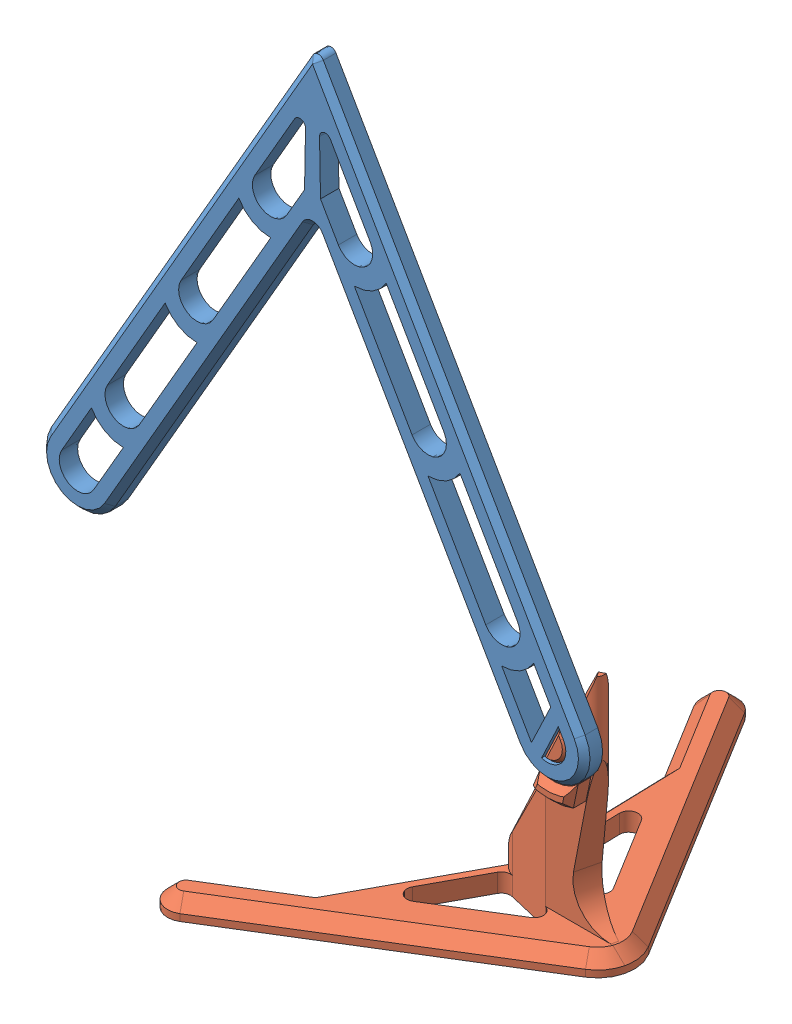
SolidWorks assembly prize_A, configuration Default. Lengths in mm.
Overall size (107.04 112.97 90.43).
2 component instances, 2 part files, 2 mates.
Components (placement in the parent):
- letter_A-1: letter_A [Default] at (-10.7459 59.4947 -8.1672) size (93.65 88.15 3.17)
- stand_A-1: stand_A [Default] at (33.734 -54.4767 -9.6356) x (0.972894 0 0.23125) z (-0.23125 0 0.972894) size (43.2 41.27 82.68)
Mates (geometry in assembly coordinates):
- Coincident1: coincident: plane of letter_A-1 through (29.7289 -23.3096 -8.1672) normal (0 0 -1); plane of stand_A-1 through (23.7442 -18.1306 -8.1672) normal (0 0 1)
- Concentric4: concentric aligned: cylinder of letter_A-1 through (29.7289 -23.3096 -4.9922) axis (0 0 -1) radius 6.35; cylinder of stand_A-1 through (29.7289 -23.3096 -4.9922) axis (0 0 -1) radius 6.45
